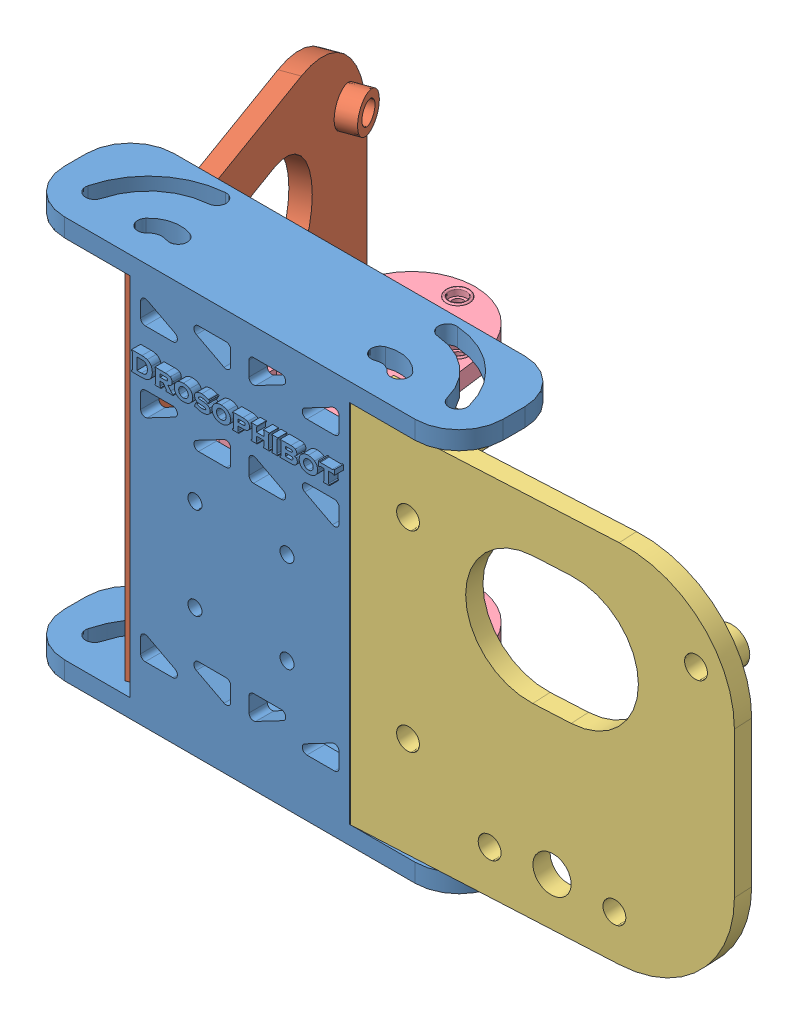
SolidWorks assembly A-Robot-003, configuration Default. Lengths in mm.
Overall size (126.38 69.85 66.06).
4 component instances, 4 part files, 10 mates.
Components (placement in the parent):
- M-Head-001-1: M-Head-001 [Default] at (4.7225 -27.5062 6.4886) size (76.2 69.85 20.64)
- M-Head-002L-1: M-Head-002L [Default] at (-25.1867 7.4188 -16.9966) x (0.34202 0 0.939693) z (-0.939693 0 0.34202) size (63.5 63.5 7.94)
- M-Head-002R-1: M-Head-002R [Default] at (55.479 7.4188 11.177) x (0.99863 0 -0.052336) z (0.052336 0 0.99863) size (63.5 63.5 7.94)
- P-Head-003-1: P-Head-003 [Default] at (4.9231 2.8438 -13.6614) x (1 0 0) z (0 1 0) size (25 37.5 48.5)
Mates (geometry in assembly coordinates):
- Angle1: planar angle = 1.22173 rad aligned: plane of Head Side Left-1 through (-25.1867 7.4188 -16.9966) normal (0.939693 0 -0.34202); plane of Head Base-1 through (-14.3275 39.1688 12.8386) normal (0 0 -1)
- Parallel1: parallel anti-aligned: line of Head Base-1 through (-14.3275 39.1688 16.0136) axis (0 -1 0); line of Head Side Left-1 through (-17.311 -24.3312 13.9245) axis (0 1 0)
- Coincident3: coincident anti-aligned: plane of Head Base-1 through (4.7225 -24.3312 6.4886) normal (0 1 0); plane of Head Side Left-1 through (-39.0293 -24.3312 -45.7459) normal (0 -1 0)
- Coincident7: coincident anti-aligned: line of Head Base-1 through (-14.3275 39.1688 12.8386) axis (0 -1 0); line of Head Side Left-1 through (-14.3275 -21.1562 12.8386) axis (0 1 0)
- Coincident13: coincident anti-aligned: plane of Head Base-1 through (4.7225 -24.3312 6.4886) normal (0 1 0); plane of Head Side Right-1 through (23.9387 -24.3312 16.0093) normal (0 -1 0)
- Coincident14: coincident aligned: line of Head Base-1 through (23.7725 39.1688 12.8386) axis (0 -1 0); line of Head Side Right-1 through (23.7725 35.9938 12.8386) axis (0 -1 0)
- Angle2: planar angle = 0.05236 rad anti-aligned: plane of Head Side Right-1 through (23.9387 39.1688 16.0093) normal (-0.99863 0 0.052336); plane of Head Base-1 through (23.7725 39.1688 16.0136) normal (1 0 0)
- Concentric8: concentric anti-aligned: cylinder of Head Base-1 through (-3.0772 10.8438 12.8386) axis (0 0 -1) radius 1.2192; cylinder of F2 Bracket-1 through (-3.0772 10.8438 2.8386) axis (0 0 1) radius 1
- Concentric9: concentric anti-aligned: cylinder of Head Base-1 through (12.9228 -5.1562 12.8386) axis (0 0 -1) radius 1.2192; cylinder of F2 Bracket-1 through (12.9228 -5.1562 2.8386) axis (0 0 1) radius 1
- Coincident20: coincident anti-aligned: plane of Head Base-1 through (-14.3275 39.1688 12.8386) normal (0 0 -1); plane of F2 Bracket-1 through (-7.5769 26.8438 12.8386) normal (0 0 1)
